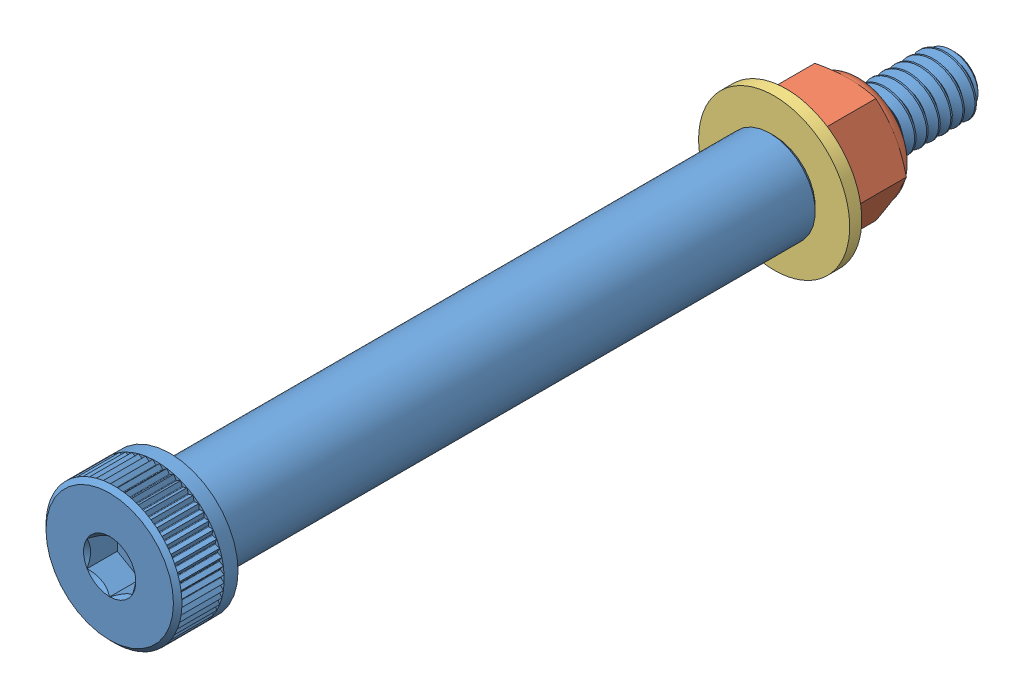
SolidWorks assembly 000012_REVD_0.375 DIA SHOULDER SCREW W_0.25-20 THDS, configuration Default. Lengths in mm.
Overall size (15.88 15.88 89.74).
3 component instances, 3 part files, 6 mates.
Components (placement in the parent):
- 000012-45_REVD_0.375 DIA X 2.5 SHOULDER SCREW 0.25-20_FLIP-1: 000012-45_REVD_0.375 DIA X 2.5 SHOULDER SCREW 0.25-20_FLIP [97345A252] at origin size (14.29 14.29 89.74)
- 000012-40_REVD_NYLON-INSERT LOCKNUT, 0.25-20 UNC-1: 000012-40_REVD_NYLON-INSERT LOCKNUT, 0.25-20 UNC [90715A125] at (0 0 -71.12) x (0 -1 0) z (1 0 0) size (11.11 8.13 12.83)
- 000012-39_REVD_USS FLAT WASHER 0.25-1: 000012-39_REVD_USS FLAT WASHER 0.25 [91950A029] at (0 0 -69.85) size (15.88 15.88 1.27)
Mates (geometry in assembly coordinates):
- Concentric3: concentric anti-aligned: cylinder of 000012-45_REVD_0.375 DIA X 2.5 SHOULDER SCREW 0.25-20_FLIP-1 through (0 0 -88.9) axis (0 0 -1) radius 4.7625; cylinder of 000012-39_REVD_USS FLAT WASHER 0.25-1 through (0 0 -71.12) axis (0 0 1) radius 3.5719
- Coincident1: coincident anti-aligned: plane of 000012-45_REVD_0.375 DIA X 2.5 SHOULDER SCREW 0.25-20_FLIP-1 through (0 -4.7625 -69.85) normal (0 0 -1); plane of 000012-39_REVD_USS FLAT WASHER 0.25-1 through (0 0 -69.85) normal (0 0 1)
- Parallel3: parallel aligned: plane of 000012-39_REVD_USS FLAT WASHER 0.25-1 through (0 0 -69.85) normal (0 1 0); plane of assembly through (0 0 0) normal (0 1 0)
- Coincident3: coincident anti-aligned: plane of 000012-40_REVD_NYLON-INSERT LOCKNUT, 0.25-20 UNC-1 through (-3.2079 -5.5563 -71.12) normal (0 0 1); plane of 000012-39_REVD_USS FLAT WASHER 0.25-1 through (0 0 -71.12) normal (0 0 -1)
- Concentric4: concentric anti-aligned: cylinder of 000012-45_REVD_0.375 DIA X 2.5 SHOULDER SCREW 0.25-20_FLIP-1 through (0 0 -88.9) axis (0 0 -1) radius 2.3247; cylinder of 000012-40_REVD_NYLON-INSERT LOCKNUT, 0.25-20 UNC-1 through (0 0 -77.8108) axis (0 0 1) radius 2.6099
- Coincident4: coincident anti-aligned: plane of 000012-40_REVD_NYLON-INSERT LOCKNUT, 0.25-20 UNC-1; plane of assembly through (0 0 0) normal (0 1 0)
